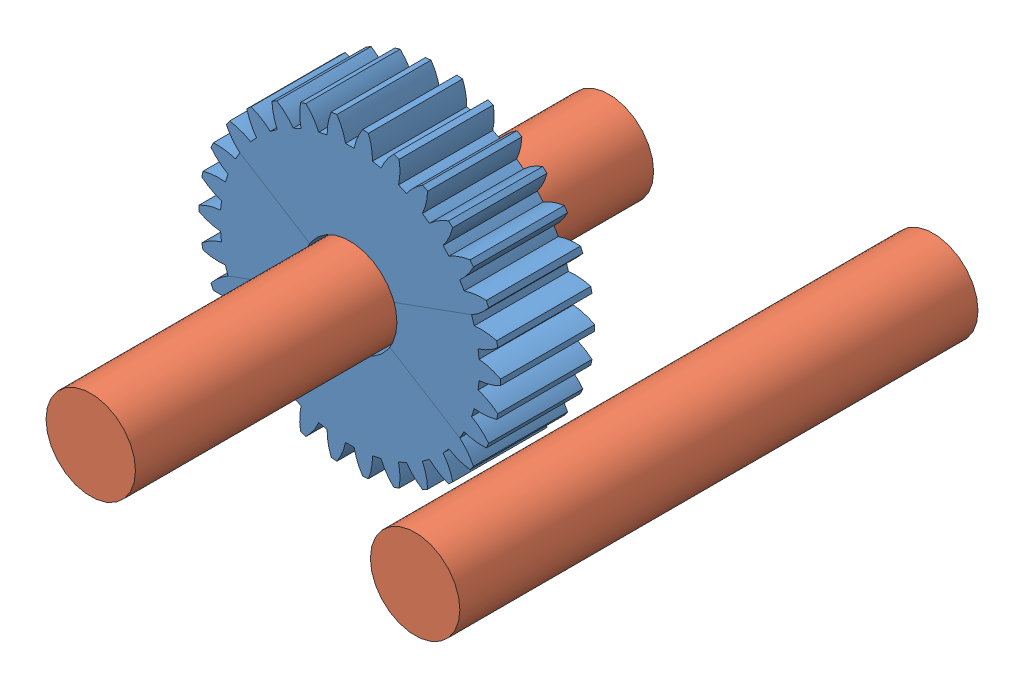
SolidWorks assembly Gear-Assembly-Split, configuration Default. Lengths in mm.
Overall size (64 63.76 20).
4 component instances, 2 part files, 9 mates.
Components (placement in the parent):
- Gear^Gear-Assembly-Split-3: Gear^Gear-Assembly-Split [Default] at origin size (64 63.76 20) (virtual)
- Shaft^Gear-Assembly-Split-1: Shaft^Gear-Assembly-Split [Default] at (0 0 10) size (19 19 110) (virtual)
- Gear^Gear-Assembly-Split-4: Gear^Gear-Assembly-Split [Default] at (60 0 0) x (0.949112 0.314939 0) z (0 0 1) size (64 63.76 20) (hidden, virtual)
- Shaft^Gear-Assembly-Split-2: Shaft^Gear-Assembly-Split [Default] at (60 0 1.1363) size (19 19 110) (virtual)
Mates (geometry in assembly coordinates):
- InPlace1: in place: plane of Gear^Gear-Assembly-Split-3 through (0 0 0) normal (0 0 1); moOrthogonalPlaneRef_w of Gear^Gear-Assembly-Split-3 through (0 0 0) normal (0 1 0); plane of Gear^Gear-Assembly-Split-3 through (0 0 0) normal (1 0 0); unknown of Gear^Gear-Assembly-Split-3
- Coincident1: coincident aligned: 
- Coincident2: coincident aligned: plane of Part1^Assem2-1 through (0 0 0) normal (0 1 0)
- Coincident3: coincident anti-aligned: plane of Part1^Assem2-1 through (0 0 0) normal (1 0 0)
- Coincident8: coincident: line of Pinion^Assem2-2 through (60 0 10) axis (0 0 -1)
- Distance1: distance = 40 mm: cylinder of Pinion^Assem2-1 through (0 0 -10) axis (0 0 1) radius 10; cylinder of Pinion^Assem2-2 through (60 0 -10) axis (0 0 1) radius 10
- Coincident10: coincident: line of Pinion^Assem2-1 through (0 0 10) axis (0 0 -1)
- Concentric2: concentric anti-aligned: cylinder of Pinion^Assem2-1 through (0 0 -10) axis (0 0 1) radius 10; cylinder of Shaft^Gear-Assembly-1 through (0 0 65) axis (0 0 -1) radius 9.5
- Concentric3: concentric anti-aligned: cylinder of Pinion^Assem2-2 through (60 0 -10) axis (0 0 1) radius 10; cylinder of Shaft^Gear-Assembly-2 through (60 0 56.1363) axis (0 0 -1) radius 9.5
